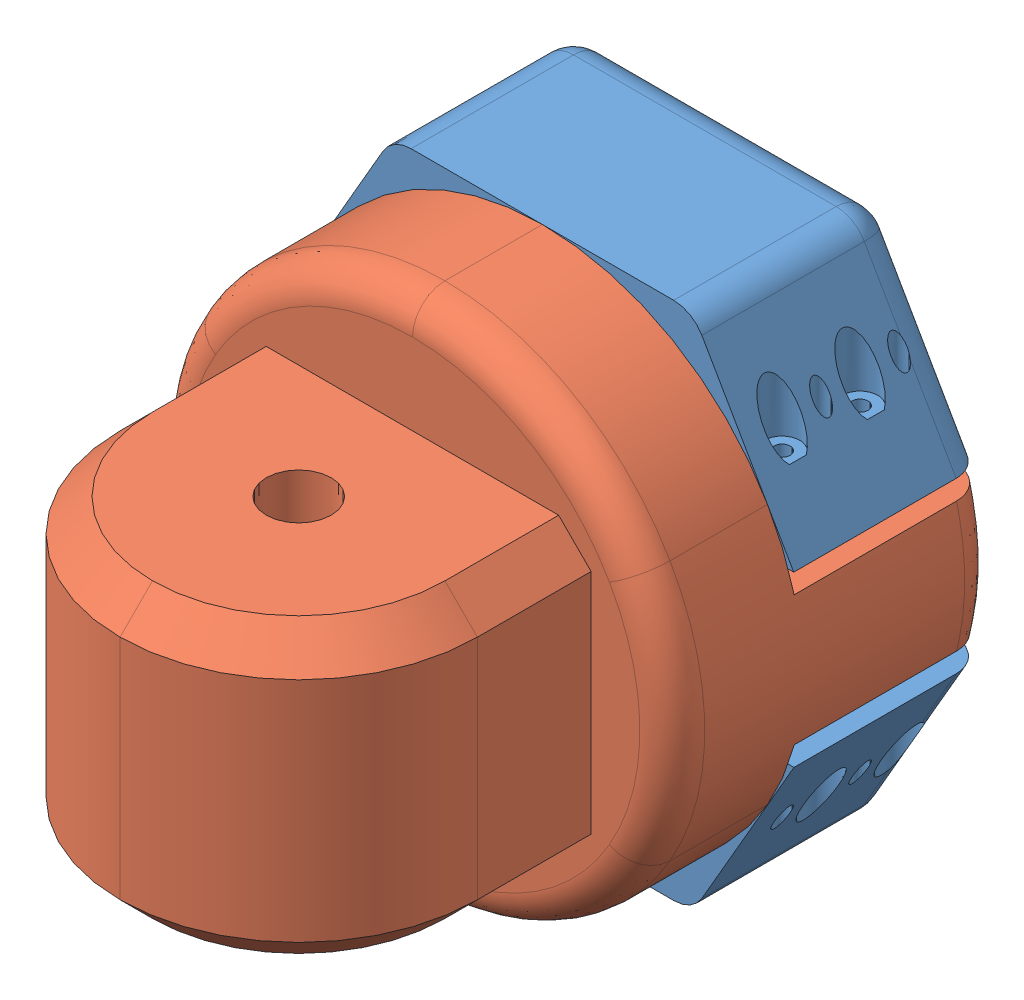
SolidWorks assembly Pipe holder main finally, configuration 기본. Lengths in mm.
Overall size (80 80 95.31).
3 component instances, 2 part files, 5 mates.
Components (placement in the parent):
- top,bottom this-1: top,bottom this [기본] at (-35.7258 36.7017 62.3649) size (77.36 27 30)
- pipe holder this-1: pipe holder this [기본] at (-35.7588 36.7017 62.3649) x (0 0 1) z (-1 0 0) size (95 80 92.38)
- top,bottom this-3: top,bottom this [기본] at (-35.7588 36.7017 92.3649) x (1 0 0) z (0 0 -1) size (77.36 27 30)
Mates (geometry in assembly coordinates):
- 일치6: coincident: plane of top,bottom this-1 through (-35.7258 36.7017 92.3649) normal (0 0 1); plane of pipe holder this-1 through (-35.7588 36.7017 92.3649) normal (0 0 -1)
- 일치7: coincident: line of pipe holder this-1 through (-12.6648 -3.2983 92.3649) axis (-1 0 0); line of top,bottom this-1 through (-55.933 -3.2983 92.3649) axis (1 0 0)
- 일치15: coincident: plane of pipe holder this-1 through (-35.7588 36.7017 92.3649) normal (0 0 -1); plane of top,bottom this-3 through (-35.7588 36.7017 92.3649) normal (0 0 1)
- 일치16: coincident: plane of pipe holder this-1 through (-35.7588 36.7017 92.3649) normal (0 0 -1); line of top,bottom this-3 through (-11.2214 74.2017 92.3649) axis (0.5 -0.866025 0)
- 일치17: coincident: line of pipe holder this-1 through (-76.1733 46.7017 92.3649) axis (0.5 0.866025 0); line of top,bottom this-3 through (-74.4413 49.7017 92.3649) axis (0.5 0.866025 0)
